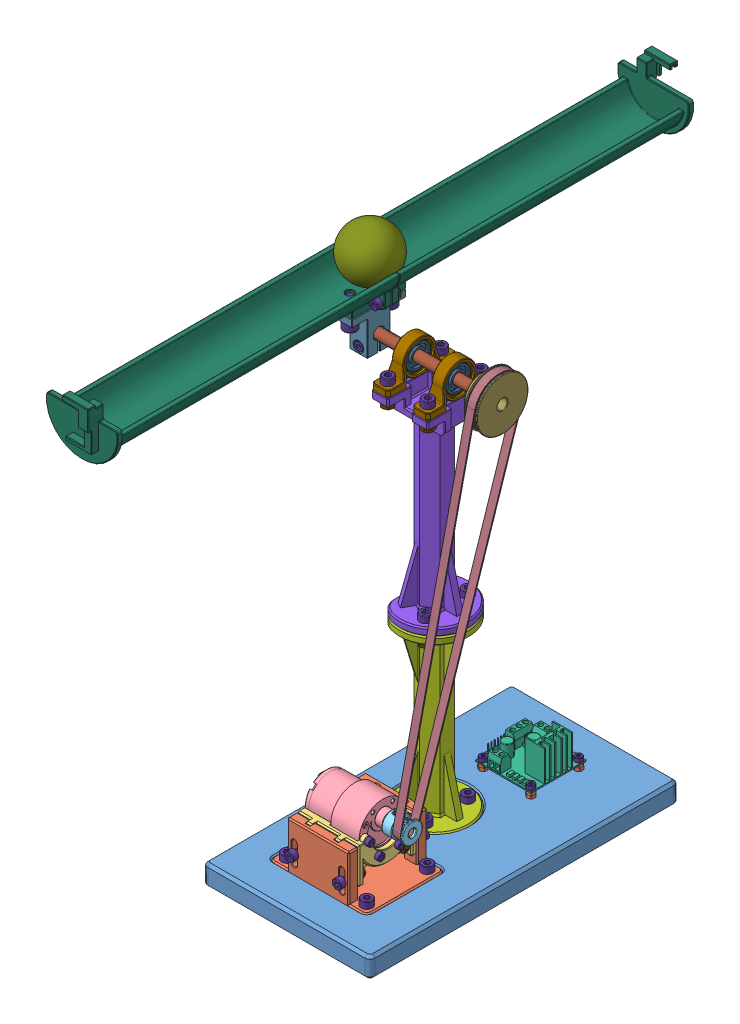
SolidWorks assembly ball and beam assembly, configuration Default. Lengths in mm.
Overall size (160.01 394.6 464.4).
84 component instances, 20 part files, 193 mates.
Components (placement in the parent):
- mount-1: mount [Default] at (98.4579 141.4502 221.2931) size (130 16 240)
- motor slider-1: motor slider [Default] at (95.4579 157.4502 283.2931) size (76 41 61)
- motor frame-1: motor frame [Default] at (93.2579 192.9369 283.2931) size (48 31 53)
- JGB37-520 motor-1: JGB37-520 motor [Default] at (115.4579 192.9369 283.2931) x (0 0 -1) z (1 0 0) size (37 37 70.88)
- 6mm 20-teeth gear-1: 6mm 20-teeth gear [Default] at (122.4579 199.9369 283.2931) x (0 0 -1) z (0 1 0) size (16.01 16 16.01)
- L298N driver-1: L298N driver [Default] at (119.9579 162.2502 172.7931) x (0 0 1) z (-1 0 0) size (43 25 43)
- lower pillar-1: lower pillar [Default] at (85.4579 151.4502 213.2931) size (54 138 54)
- upper pillar-1: upper pillar [Default] at (85.4579 289.4502 213.2931) size (49 150 54)
- bearing frame-1: bearing frame [Default] at (69.8579 453.4502 213.2931) x (0 0 1) z (-1 0 0) size (54 27 13)
- bearing frame-2: bearing frame [Default] at (100.9579 453.4502 213.2931) x (0 0 -1) z (1 0 0) size (54 27 13)
- ball bearing-1: ball bearing [Default] at (69.8579 453.4502 213.2931) x (-1 0 0) z (0 -0.088939 -0.996037) size (6 19 19)
- ball bearing-2: ball bearing [Default] at (100.9579 453.4502 213.2931) x (1 0 0) z (0 -0.000004 1) size (6 19 19)
- shaft-1: shaft [Default] at (78.4579 453.4502 213.2931) x (1 0 0) z (0 -0.931517 -0.363698) size (100 8 8)
- 8mm 60-teeth gear-1: 8mm 60-teeth gear [Default] at (120.4579 453.4502 213.2931) x (0 0 -1) z (0 1 0) size (40 16 40)
- timing belt-1: timing belt [Default] at (135.9579 199.9369 283.2931) x (0 0.963929 -0.26616) z (0 0.26616 0.963929) size (289.55 6 39.3)
- holder-1: holder [Default] at (42.4579 467.0502 213.2931) x (0 0 1) z (-1 0 0) size (42 32.6 14)
- half guide-1: half guide [Default] at (35.4579 505.0502 213.2931) size (55.43 48 232.2)
- half guide-2: half guide [Default] at (35.4579 505.0502 213.2931) x (-1 0 0) z (0 0 -1) size (55.43 48 232.2)
- ball-1: ball [Default] at (35.4579 504.8502 213.2931) x (0.673328 -0.738892 -0.025844) z (-0.222182 -0.168881 -0.960268) size (40 40 40)
- socket head cap screw_din-39: socket head cap screw_din [DIN 912 M6 x 16 --- 16N] at (35.4579 461.0502 228.7931) x (0 1 0) z (-0.089233 0 0.996011) size (22 10 10)
- socket head cap screw_din-40: socket head cap screw_din [DIN 912 M6 x 16 --- 16N] at (35.4579 461.0502 197.7931) x (0 1 0) z (0.266539 0 0.963824) size (22 10 10)
- socket head cap screw_din-23: socket head cap screw_din [DIN 912 M5 x 16 --- 16N] at (126.4579 162.4502 259.7931) x (0 -1 0) z (0.988894 0 -0.14862) size (21 8.5 8.5)
- socket head cap screw_din-24: socket head cap screw_din [DIN 912 M5 x 16 --- 16N] at (126.4579 162.4502 306.7931) x (0 -1 0) z (-0.960711 0 0.277552) size (21 8.5 8.5)
- socket head cap screw_din-25: socket head cap screw_din [DIN 912 M5 x 16 --- 16N] at (64.4579 162.4502 306.7931) x (0 -1 0) z (0.875234 0 -0.4837) size (21 8.5 8.5)
- socket head cap screw_din-26: socket head cap screw_din [DIN 912 M5 x 16 --- 16N] at (64.4579 162.4502 259.7931) x (0 -1 0) z (0.980307 0 0.197478) size (21 8.5 8.5)
- socket head cap screw_din-27: socket head cap screw_din [DIN 912 M5 x 16 --- 16N] at (94.9579 162.4502 229.7476) x (0 -1 0) z (0.778512 0 -0.62763) size (21 8.5 8.5)
- socket head cap screw_din-28: socket head cap screw_din [DIN 912 M5 x 16 --- 16N] at (66.4579 162.4502 213.2931) x (0 -1 0) z (0.181274 0 0.983433) size (21 8.5 8.5)
- socket head cap screw_din-29: socket head cap screw_din [DIN 912 M5 x 16 --- 16N] at (94.9579 162.4502 196.8386) x (0 -1 0) z (0.963689 0 -0.267027) size (21 8.5 8.5)
- hex nut style 1 gradeab_din-14: hex nut style 1 gradeab_din [Hexagon Nut ISO 4032 - M5 - D - N] at (64.4579 141.7502 259.7931) x (-0.560846 0 -0.82792) z (0 -1 0) size (8 9.24 4.7)
- hex nut style 1 gradeab_din-15: hex nut style 1 gradeab_din [Hexagon Nut ISO 4032 - M5 - D - N] at (126.4579 141.7502 259.7931) x (0.993337 0 0.115248) z (0 -1 0) size (8 9.24 4.7)
- hex nut style 1 gradeab_din-16: hex nut style 1 gradeab_din [Hexagon Nut ISO 4032 - M5 - D - N] at (126.4579 141.7502 306.7931) x (0.982792 0 -0.184716) z (0 -1 0) size (8 9.24 4.7)
- hex nut style 1 gradeab_din-17: hex nut style 1 gradeab_din [Hexagon Nut ISO 4032 - M5 - D - N] at (64.4579 141.7502 306.7931) x (0.998993 0 0.044877) z (0 -1 0) size (8 9.24 4.7)
- hex nut style 1 gradeab_din-22: hex nut style 1 gradeab_din [Hexagon Nut ISO 4032 - M5 - D - N] at (66.4579 146.4502 213.2931) x (0.894625 0 0.446817) z (0 1 0) size (8 9.24 4.7)
- hex nut style 1 gradeab_din-23: hex nut style 1 gradeab_din [Hexagon Nut ISO 4032 - M5 - D - N] at (94.9579 146.4502 196.8386) x (-0.894625 0 -0.446817) z (0 1 0) size (8 9.24 4.7)
- hex nut style 1 gradeab_din-24: hex nut style 1 gradeab_din [Hexagon Nut ISO 4032 - M5 - D - N] at (94.9579 146.4502 229.7476) x (0.894625 0 0.446817) z (0 1 0) size (8 9.24 4.7)
- socket head cap screw_din-44: socket head cap screw_din [DIN 912 M5 x 16 --- 16N] at (94.9579 300.4502 229.7476) x (0 -1 0) z (0.181274 0 0.983433) size (21 8.5 8.5)
- socket head cap screw_din-47: socket head cap screw_din [DIN 912 M5 x 16 --- 16N] at (94.9579 300.4502 196.8386) x (0 -1 0) z (0.83914 0 -0.543915) size (21 8.5 8.5)
- hex nut style 1 gradeab_din-28: hex nut style 1 gradeab_din [Hexagon Nut ISO 4032 - M5 - D - N] at (94.9579 278.7502 196.8386) x (0.993337 0 0.115248) z (0 -1 0) size (8 9.24 4.7)
- hex nut style 1 gradeab_din-29: hex nut style 1 gradeab_din [Hexagon Nut ISO 4032 - M5 - D - N] at (94.9579 278.7502 229.7476) x (0.993337 0 0.115248) z (0 -1 0) size (8 9.24 4.7)
- socket head cap screw_din-30: socket head cap screw_din [DIN 912 M5 x 16 --- 16N] at (69.9579 449.4502 192.7931) x (0 -1 0) z (0 0 1) size (21 8.5 8.5)
- socket head cap screw_din-31: socket head cap screw_din [DIN 912 M5 x 16 --- 16N] at (100.9579 449.4502 233.7931) x (0 -1 0) z (0 0 1) size (21 8.5 8.5)
- socket head cap screw_din-32: socket head cap screw_din [DIN 912 M5 x 16 --- 16N] at (69.8579 449.4502 233.7931) x (0 -1 0) z (0 0 1) size (21 8.5 8.5)
- socket head cap screw_din-33: socket head cap screw_din [DIN 912 M5 x 16 --- 16N] at (100.9579 449.4502 192.7931) x (0 -1 0) z (-0.000002 0 1) size (21 8.5 8.5)
- hex nut style 1 gradeab_din-18: hex nut style 1 gradeab_din [Hexagon Nut ISO 4032 - M5 - D - N] at (69.9579 433.4502 192.7931) x (-0.247009 0 -0.969013) z (0 1 0) size (8 9.24 4.7)
- hex nut style 1 gradeab_din-19: hex nut style 1 gradeab_din [Hexagon Nut ISO 4032 - M5 - D - N] at (69.8579 433.4502 233.7931) x (-0.247009 0 -0.969013) z (0 1 0) size (8 9.24 4.7)
- hex nut style 1 gradeab_din-20: hex nut style 1 gradeab_din [Hexagon Nut ISO 4032 - M5 - D - N] at (100.9579 428.7502 192.7931) x (-0.247009 0 0.969013) z (0 -1 0) size (8 9.24 4.7)
- hex nut style 1 gradeab_din-21: hex nut style 1 gradeab_din [Hexagon Nut ISO 4032 - M5 - D - N] at (100.9579 428.7502 233.7931) x (-0.247009 0 0.969013) z (0 -1 0) size (8 9.24 4.7)
- socket head cap screw_din-15: socket head cap screw_din [DIN 912 M4 x 16 --- 16N] at (113.9579 170.4369 317.7931) x (0 0 -1) z (0.995609 -0.093607 0) size (20 7 7)
- socket head cap screw_din-16: socket head cap screw_din [DIN 912 M4 x 16 --- 16N] at (76.9579 170.4369 317.7931) x (0 0 -1) z (0.955528 0.2949 0) size (20 7 7)
- socket head cap screw_din-17: socket head cap screw_din [DIN 912 M4 x 16 --- 16N] at (76.9579 170.4369 248.7931) x (0 0 1) z (-0.883816 -0.467834 0) size (20 7 7)
- socket head cap screw_din-18: socket head cap screw_din [DIN 912 M4 x 16 --- 16N] at (113.9579 170.4369 248.7931) x (0 0 1) z (0.883816 0.467834 0) size (20 7 7)
- hex nut style 1 gradeab_din-10: hex nut style 1 gradeab_din [Hexagon Nut ISO 4032 - M4 - D - N] at (113.9579 170.4369 301.8931) x (-0.247009 0.969013 0) z (0 0 1) size (7 8.08 3.2)
- hex nut style 1 gradeab_din-11: hex nut style 1 gradeab_din [Hexagon Nut ISO 4032 - M4 - D - N] at (113.9579 170.4369 264.6931) x (0.857592 0.514331 0) z (0 0 -1) size (7 8.08 3.2)
- hex nut style 1 gradeab_din-12: hex nut style 1 gradeab_din [Hexagon Nut ISO 4032 - M4 - D - N] at (76.9579 170.4369 267.8931) size (7 8.08 3.2)
- hex nut style 1 gradeab_din-13: hex nut style 1 gradeab_din [Hexagon Nut ISO 4032 - M4 - D - N] at (76.9579 170.4369 298.6931) x (-0.934219 0.356701 0) z (0 0 -1) size (7 8.08 3.2)
- socket head cap screw_din-42: socket head cap screw_din [DIN 912 M4 x 16 --- 16N] at (23.4579 479.5566 222.7931) x (0 0 -1) z (0.771294 -0.636479 0) size (20 7 7)
- socket head cap screw_din-41: socket head cap screw_din [DIN 912 M4 x 16 --- 16N] at (47.4579 479.5566 222.7931) x (0 0 -1) z (0.771294 -0.636479 0) size (20 7 7)
- hex nut style 1 gradeab_din-25: hex nut style 1 gradeab_din [Hexagon Nut ISO 4032 - M4 - D - N] at (23.4579 479.5566 204.5931) x (-0.554504 0.832181 0) z (0 0 -1) size (7 8.08 3.2)
- hex nut style 1 gradeab_din-27: hex nut style 1 gradeab_din [Hexagon Nut ISO 4032 - M4 - D - N] at (47.4579 479.5566 204.5931) x (-0.554504 0.832181 0) z (0 0 -1) size (7 8.08 3.2)
- socket head cap screw_din-43: socket head cap screw_din [DIN 912 M4 x 16 --- 16N] at (35.4579 445.4502 222.2931) x (0 0 -1) z (0.771294 -0.636479 0) size (20 7 7)
- socket set screw flat point_din-1: socket set screw flat point_din [DIN 913 - M4 x 5-N] at (126.2079 207.9369 283.2931) x (0 -1 0) z (-0.046067 0 0.998938) size (5 4 4)
- socket set screw flat point_din-2: socket set screw flat point_din [DIN 913 - M4 x 5-N] at (126.2079 199.9369 275.2931) x (0 0 1) z (-0.067896 -0.997692 0) size (5 4 4)
- socket set screw flat point_din-3: socket set screw flat point_din [DIN 913 - M4 x 5-N] at (125.4579 462.4502 213.2931) x (0 -1 0) z (0.980778 0 0.195125) size (5 4 4)
- socket set screw flat point_din-4: socket set screw flat point_din [DIN 913 - M4 x 5-N] at (125.4579 453.4502 204.2931) x (0 0 1) z (0.974269 -0.22539 0) size (5 4 4)
- socket head cap screw_din-5: socket head cap screw_din [DIN 912 M3 x 16 --- 16N] at (116.9579 166.2502 169.7931) x (0 -1 0) z (-0.613586 0 -0.789628) size (19 5.5 5.5)
- socket head cap screw_din-7: socket head cap screw_din [DIN 912 M3 x 16 --- 16N] at (116.9579 166.2502 132.7931) x (0 -1 0) z (0 0 1) size (19 5.5 5.5)
- socket head cap screw_din-8: socket head cap screw_din [DIN 912 M3 x 16 --- 16N] at (79.9579 166.2502 169.7931) x (0 -1 0) z (-0.000315 0 1) size (19 5.5 5.5)
- socket head cap screw_din-9: socket head cap screw_din [DIN 912 M3 x 16 --- 16N] at (79.9579 166.2502 132.7931) x (0 -1 0) z (0 0 1) size (19 5.5 5.5)
- hex nut style 1 gradeab_iso-11: hex nut style 1 gradeab_iso [ISO - 4032 - M3 - D - N] at (116.9579 159.8502 132.7931) x (0.674492 0 -0.738282) z (0 -1 0) size (5.5 6.35 2.4)
- hex nut style 1 gradeab_iso-12: hex nut style 1 gradeab_iso [ISO - 4032 - M3 - D - N] at (116.9579 159.8502 169.7931) x (0.674492 0 -0.738282) z (0 -1 0) size (5.5 6.35 2.4)
- hex nut style 1 gradeab_iso-13: hex nut style 1 gradeab_iso [ISO - 4032 - M3 - D - N] at (79.9579 159.8502 169.7931) x (0.674492 0 -0.738282) z (0 -1 0) size (5.5 6.35 2.4)
- hex nut style 1 gradeab_iso-14: hex nut style 1 gradeab_iso [ISO - 4032 - M3 - D - N] at (79.9579 159.8502 132.7931) x (0.674492 0 -0.738282) z (0 -1 0) size (5.5 6.35 2.4)
- hex nut style 1 gradeab_iso-1: hex nut style 1 gradeab_iso [ISO - 4032 - M3 - D - N] at (79.9579 159.8502 169.7931) x (1 0 0) z (0 1 0) size (5.5 6.35 2.4)
- hex nut style 1 gradeab_iso-3: hex nut style 1 gradeab_iso [ISO - 4032 - M3 - D - N] at (116.9579 159.8502 132.7931) x (1 0 0) z (0 1 0) size (5.5 6.35 2.4)
- hex nut style 1 gradeab_iso-4: hex nut style 1 gradeab_iso [ISO - 4032 - M3 - D - N] at (116.9579 157.4502 169.7931) x (0.674492 0 -0.738282) z (0 -1 0) size (5.5 6.35 2.4)
- hex nut style 1 gradeab_iso-5: hex nut style 1 gradeab_iso [ISO - 4032 - M3 - D - N] at (79.9579 159.8502 132.7931) x (1 0 0) z (0 1 0) size (5.5 6.35 2.4)
- hex nut style 1 gradeab_iso-6: hex nut style 1 gradeab_iso [ISO - 4032 - M3 - D - N] at (116.9579 152.4502 169.7931) x (-0.966898 0 -0.255164) z (0 1 0) size (5.5 6.35 2.4)
- hex nut style 1 gradeab_iso-7: hex nut style 1 gradeab_iso [ISO - 4032 - M3 - D - N] at (79.9579 152.4502 169.7931) x (0.901145 0 -0.433517) z (0 1 0) size (5.5 6.35 2.4)
- hex nut style 1 gradeab_iso-8: hex nut style 1 gradeab_iso [ISO - 4032 - M3 - D - N] at (79.9579 152.4502 132.7931) x (0.990081 0 -0.140499) z (0 1 0) size (5.5 6.35 2.4)
- hex nut style 1 gradeab_iso-9: hex nut style 1 gradeab_iso [ISO - 4032 - M3 - D - N] at (116.9579 152.4502 132.7931) x (0.649349 0 -0.76049) z (0 1 0) size (5.5 6.35 2.4)
- socket head cap screw_din-34: socket head cap screw_din [DIN 912 M3 x 12 --- 12N] at (122.4579 179.5135 291.0431) x (-1 0 0) z (0 -0.924225 -0.381849) size (15 5.5 5.5)
- socket head cap screw_din-35: socket head cap screw_din [DIN 912 M3 x 12 --- 12N] at (122.4579 179.5135 275.5431) x (-1 0 0) z (0 -0.924225 -0.381849) size (15 5.5 5.5)
- socket head cap screw_din-36: socket head cap screw_din [DIN 912 M3 x 12 --- 12N] at (122.4579 192.9369 298.7931) x (-1 0 0) z (0 -0.924225 -0.381849) size (15 5.5 5.5)
- socket head cap screw_din-37: socket head cap screw_din [DIN 912 M3 x 12 --- 12N] at (122.4579 192.9369 267.7931) x (-1 0 0) z (0 -0.924225 -0.381849) size (15 5.5 5.5)
Mates (geometry in assembly coordinates):
- Concentric1: concentric: cylinder of mount-1 through (126.4579 141.4502 306.7931) axis (0 1 0) radius 2.6; cylinder of motor slider-1 through (126.4579 88.8643 306.7931) axis (0 1 0) radius 2.6
- Concentric2: concentric: cylinder of mount-1 through (64.4579 141.4502 259.7931) axis (0 1 0) radius 2.6; cylinder of motor slider-1 through (64.4579 88.8643 259.7931) axis (0 1 0) radius 2.6
- Coincident2: coincident: plane of motor slider-1 through (95.4579 157.4502 283.2931) normal (0 0 1); plane of motor frame-1 through (93.2579 192.9369 283.2931) normal (0 0 1)
- Tangent1: tangent: plane of motor slider-1 through (111.9079 177.9502 252.7931) normal (1 0 0); cylinder of motor frame-1 through (113.9579 170.4369 260.6911) axis (0 0 1) radius 2.05
- Coincident4: coincident: plane of motor slider-1 through (119.4579 157.4502 283.2931) normal (1 0 0); plane of motor frame-1 through (119.4579 192.9369 267.7931) normal (1 0 0)
- Coincident5: coincident: plane of motor slider-1 through (71.4579 157.4502 283.2931) normal (-1 0 0); plane of motor frame-1 through (71.4579 192.9369 260.6931) normal (-1 0 0)
- LimitDistance2: limit distance = 0.5133 mm: axis of motor frame-1 through (113.9579 170.4369 302.3931) axis (0 0 1); axis of motor slider-1 through (113.9579 170.9502 253.2931) axis (0 0 1)
- Coincident6: coincident: axis of motor frame-1 through (111.9579 192.9369 283.2931) axis (-1 0 0); axis of JGB37-520 motor-1 through (93.4579 192.9369 283.2931) axis (1 0 0)
- Concentric3: concentric: cylinder of motor frame-1 through (71.4569 192.9369 298.7931) axis (1 0 0) radius 1.55; cylinder of JGB37-520 motor-1 through (115.4579 192.9369 298.7931) axis (1 0 0) radius 1.25
- Coincident7: coincident: plane of motor frame-1 through (115.4579 192.9369 267.7931) normal (-1 0 0); plane of JGB37-520 motor-1 through (115.4579 192.9369 283.2931) normal (1 0 0)
- Concentric4: concentric: cylinder of L298N driver-1 through (79.9579 163.2502 169.7931) axis (0 -1 0) radius 1.5; cylinder of mount-1 through (79.9579 141.4502 169.7931) axis (0 1 0) radius 1.55
- Concentric5: concentric: cylinder of mount-1 through (116.9579 141.4502 169.7931) axis (0 1 0) radius 1.55; cylinder of L298N driver-1 through (116.9579 163.2502 169.7931) axis (0 -1 0) radius 1.5
- Concentric6: concentric: cylinder of mount-1 through (116.9579 141.4502 169.7931) axis (0 1 0) radius 1.55; cylinder of socket head cap screw_din-5 through (116.9579 198.0002 169.7931) axis (0 1 0) radius 1.5
- Coincident9: coincident: plane of L298N driver-1 through (119.9579 163.2502 172.7931) normal (0 1 0); plane of socket head cap screw_din-5 through (114.7865 163.2502 171.4804) normal (0 -1 0)
- Concentric7: concentric: cylinder of mount-1 through (116.9579 141.4502 132.7931) axis (0 1 0) radius 1.55; cylinder of socket head cap screw_din-7 through (116.9579 198.0002 132.7931) axis (0 1 0) radius 1.5
- Concentric8: concentric: cylinder of mount-1 through (79.9579 141.4502 132.7931) axis (0 1 0) radius 1.55; cylinder of socket head cap screw_din-9 through (79.9579 198.0002 132.7931) axis (0 1 0) radius 1.5
- Concentric9: concentric: cylinder of mount-1 through (79.9579 141.4502 169.7931) axis (0 1 0) radius 1.55; cylinder of socket head cap screw_din-8 through (79.9579 198.0002 169.7931) axis (0 1 0) radius 1.5
- Coincident10: coincident: plane of L298N driver-1 through (119.9579 163.2502 172.7931) normal (0 1 0); plane of socket head cap screw_din-7 through (119.7079 163.2502 132.7931) normal (0 -1 0)
- Coincident11: coincident: plane of L298N driver-1 through (119.9579 163.2502 172.7931) normal (0 1 0); plane of socket head cap screw_din-9 through (82.7079 163.2502 132.7931) normal (0 -1 0)
- Coincident12: coincident: plane of L298N driver-1 through (119.9579 163.2502 172.7931) normal (0 1 0); plane of socket head cap screw_din-8 through (82.7079 163.2502 169.7939) normal (0 -1 0)
- Concentric10: concentric: cylinder of socket head cap screw_din-5 through (116.9579 198.0002 169.7931) axis (0 1 0) radius 1.5; cylinder of hex nut style 1 gradeab_iso-4 through (116.9579 159.8502 169.7931) axis (0 -1 0) radius 1.25
- Coincident13: coincident: plane of mount-1 through (98.4579 157.4502 221.2931) normal (0 1 0); plane of hex nut style 1 gradeab_iso-4 through (119.3023 157.4502 171.9349) normal (0 -1 0)
- Coincident14: coincident: plane of mount-1 through (98.4579 157.4502 221.2931) normal (0 1 0); plane of hex nut style 1 gradeab_iso-3 through (116.9579 157.4502 129.6176) normal (0 -1 0)
- Concentric11: concentric: cylinder of socket head cap screw_din-7 through (116.9579 198.0002 132.7931) axis (0 1 0) radius 1.5; cylinder of hex nut style 1 gradeab_iso-3 through (116.9579 157.4502 132.7931) axis (0 1 0) radius 1.25
- Coincident15: coincident: plane of mount-1 through (98.4579 157.4502 221.2931) normal (0 1 0); plane of hex nut style 1 gradeab_iso-5 through (79.9579 157.4502 129.6176) normal (0 -1 0)
- Concentric12: concentric: cylinder of socket head cap screw_din-9 through (79.9579 198.0002 132.7931) axis (0 1 0) radius 1.5; cylinder of hex nut style 1 gradeab_iso-5 through (79.9579 157.4502 132.7931) axis (0 1 0) radius 1.25
- Coincident16: coincident: plane of mount-1 through (98.4579 157.4502 221.2931) normal (0 1 0); plane of hex nut style 1 gradeab_iso-1 through (79.9579 157.4502 166.6176) normal (0 -1 0)
- Concentric13: concentric: cylinder of socket head cap screw_din-8 through (79.9579 198.0002 169.7931) axis (0 1 0) radius 1.5; cylinder of hex nut style 1 gradeab_iso-1 through (79.9579 157.4502 169.7931) axis (0 1 0) radius 1.25
- Concentric14: concentric: cylinder of socket head cap screw_din-5 through (116.9579 198.0002 169.7931) axis (0 1 0) radius 1.5; cylinder of hex nut style 1 gradeab_iso-6 through (116.9579 150.0502 169.7931) axis (0 1 0) radius 1.25
- Concentric15: concentric: cylinder of socket head cap screw_din-7 through (116.9579 198.0002 132.7931) axis (0 1 0) radius 1.5; cylinder of hex nut style 1 gradeab_iso-9 through (116.9579 150.0502 132.7931) axis (0 1 0) radius 1.25
- Concentric16: concentric: cylinder of socket head cap screw_din-9 through (79.9579 198.0002 132.7931) axis (0 1 0) radius 1.5; cylinder of hex nut style 1 gradeab_iso-8 through (79.9579 150.0502 132.7931) axis (0 1 0) radius 1.25
- Concentric17: concentric: cylinder of socket head cap screw_din-8 through (79.9579 198.0002 169.7931) axis (0 1 0) radius 1.5; cylinder of hex nut style 1 gradeab_iso-7 through (79.9579 150.0502 169.7931) axis (0 1 0) radius 1.25
- Coincident27: coincident: plane of mount-1 through (98.4579 151.4502 221.2931) normal (0 1 0); plane of motor slider-1 through (119.4579 151.4502 252.7931) normal (0 -1 0)
- Concentric293: concentric: cylinder of socket head cap screw_din-5 through (116.9579 198.0002 169.7931) axis (0 1 0) radius 1.5; cylinder of hex nut style 1 gradeab_iso-12 through (116.9579 162.2502 169.7931) axis (0 -1 0) radius 1.25
- Coincident353: coincident: plane of hex nut style 1 gradeab_iso-4 through (119.3023 159.8502 171.9349) normal (0 1 0); plane of hex nut style 1 gradeab_iso-12 through (119.3023 159.8502 171.9349) normal (0 -1 0)
- Coincident354: coincident: plane of hex nut style 1 gradeab_iso-1 through (79.9579 159.8502 166.6176) normal (0 1 0); plane of hex nut style 1 gradeab_iso-13 through (82.3023 159.8502 171.9349) normal (0 -1 0)
- Concentric294: concentric: cylinder of socket head cap screw_din-8 through (79.9579 198.0002 169.7931) axis (0 1 0) radius 1.5; cylinder of hex nut style 1 gradeab_iso-13 through (79.9579 162.2502 169.7931) axis (0 -1 0) radius 1.25
- Concentric295: concentric: cylinder of socket head cap screw_din-7 through (116.9579 198.0002 132.7931) axis (0 1 0) radius 1.5; cylinder of hex nut style 1 gradeab_iso-11 through (116.9579 162.2502 132.7931) axis (0 -1 0) radius 1.25
- Coincident355: coincident: plane of hex nut style 1 gradeab_iso-3 through (116.9579 159.8502 129.6176) normal (0 1 0); plane of hex nut style 1 gradeab_iso-11 through (119.3023 159.8502 134.9349) normal (0 -1 0)
- Coincident356: coincident: plane of hex nut style 1 gradeab_iso-5 through (79.9579 159.8502 129.6176) normal (0 1 0); plane of hex nut style 1 gradeab_iso-14 through (82.3023 159.8502 134.9349) normal (0 -1 0)
- Concentric296: concentric: cylinder of socket head cap screw_din-9 through (79.9579 198.0002 132.7931) axis (0 1 0) radius 1.5; cylinder of hex nut style 1 gradeab_iso-14 through (79.9579 162.2502 132.7931) axis (0 -1 0) radius 1.25
- Coincident357: coincident: plane of L298N driver-1 through (119.9579 162.2502 172.7931) normal (0 -1 0); plane of hex nut style 1 gradeab_iso-12 through (119.3023 162.2502 171.9349) normal (0 1 0)
- Concentric297: concentric: cylinder of JGB37-520 motor-1 through (136.9579 199.9369 283.2931) axis (-1 0 0) radius 3; cylinder of 6mm 20-teeth gear-1 through (122.4579 199.9369 283.2931) axis (-1 0 0) radius 3
- Distance1: distance = 1 mm: plane of JGB37-520 motor-1 through (121.4579 199.9369 283.2931) normal (1 0 0); plane of 6mm 20-teeth gear-1 through (122.4579 199.9369 283.2931) normal (-1 0 0)
- Concentric298: concentric: cylinder of 6mm 20-teeth gear-1 through (122.4579 199.9369 283.2931) axis (-1 0 0) radius 3; cylinder of timing belt-1 through (129.9579 199.9369 283.2931) axis (1 0 0) radius 6.1
- Coincident361: coincident: plane of 6mm 20-teeth gear-1 through (129.9579 199.9369 283.2931) normal (1 0 0); plane of timing belt-1 through (129.9579 453.4502 213.2931) normal (-1 0 0)
- Concentric299: concentric: cylinder of timing belt-1 through (129.9579 453.4502 213.2931) axis (1 0 0) radius 18.85; cylinder of 8mm 60-teeth gear-1 through (138.4579 453.4502 213.2931) axis (1 0 0) radius 4
- Coincident362: coincident: plane of timing belt-1 through (129.9579 453.4502 213.2931) normal (-1 0 0); plane of 8mm 60-teeth gear-1 through (129.9579 453.4502 213.2931) normal (1 0 0)
- Concentric300: concentric: cylinder of 6mm 20-teeth gear-1 through (126.2079 207.9369 283.2931) axis (0 1 0) radius 2; cylinder of socket set screw flat point_din-1 through (126.2079 220.6369 283.2931) axis (0 1 0) radius 2
- Tangent3: tangent: cylinder of JGB37-520 motor-1 through (136.9579 199.9369 283.2931) axis (-1 0 0) radius 3; plane of socket set screw flat point_din-1 through (127.4566 202.9369 283.3507) normal (0 -1 0)
- Concentric301: concentric: cylinder of 6mm 20-teeth gear-1 through (126.2079 199.9369 275.2931) axis (0 0 -1) radius 2; cylinder of socket set screw flat point_din-2 through (126.2079 199.9369 262.5931) axis (0 0 -1) radius 2
- Tangent4: tangent: cylinder of JGB37-520 motor-1 through (136.9579 199.9369 283.2931) axis (-1 0 0) radius 3; plane of socket set screw flat point_din-2 through (124.9608 200.0218 280.2931) normal (0 0 1)
- Parallel2: parallel: axis of 8mm 60-teeth gear-1 through (125.4579 459.7316 213.2931) axis (0 1 0); axis of socket set screw flat point_din-1 through (126.2079 203.6869 283.2931) axis (0 1 0)
- Concentric302: concentric: cylinder of 8mm 60-teeth gear-1 through (125.4579 467.4502 213.2931) axis (0 1 0) radius 2; cylinder of socket set screw flat point_din-3 through (125.4579 475.1502 213.2931) axis (0 1 0) radius 2
- Tangent5: tangent: cylinder of 8mm 60-teeth gear-1 through (138.4579 453.4502 213.2931) axis (1 0 0) radius 4; plane of socket set screw flat point_din-3 through (125.7019 457.4502 212.0671) normal (0 -1 0)
- Concentric303: concentric: cylinder of 8mm 60-teeth gear-1 through (125.4579 453.4502 199.2931) axis (0 0 -1) radius 2; cylinder of socket set screw flat point_din-4 through (125.4579 453.4502 191.5931) axis (0 0 -1) radius 2
- Tangent6: tangent: cylinder of 8mm 60-teeth gear-1 through (138.4579 453.4502 213.2931) axis (1 0 0) radius 4; plane of socket set screw flat point_din-4 through (125.1762 452.2324 209.2931) normal (0 0 1)
- Concentric304: concentric: cylinder of bearing frame-1 through (65.3579 453.4502 213.2931) axis (1 0 0) radius 9.5; cylinder of ball bearing-1 through (90.4954 453.4502 213.2931) axis (-1 0 0) radius 9.5
- Coincident363: coincident: plane of bearing frame-1 through (69.8579 453.4502 213.2931) normal (-1 0 0); plane of ball bearing-1 through (69.8579 453.4502 213.2931) normal (-1 0 0)
- Concentric305: concentric: cylinder of bearing frame-2 through (105.4579 453.4502 213.2931) axis (-1 0 0) radius 9.5; cylinder of ball bearing-2 through (80.3204 453.4502 213.2931) axis (1 0 0) radius 9.5
- Coincident364: coincident: plane of bearing frame-2 through (100.9579 453.4502 213.2931) normal (1 0 0); plane of ball bearing-2 through (100.9579 453.4502 213.2931) normal (1 0 0)
- Concentric306: concentric: cylinder of 8mm 60-teeth gear-1 through (138.4579 453.4502 213.2931) axis (1 0 0) radius 4; cylinder of ball bearing-1 through (90.4954 453.4502 213.2931) axis (-1 0 0) radius 4
- Concentric307: concentric: cylinder of ball bearing-1 through (90.4954 453.4502 213.2931) axis (-1 0 0) radius 4; cylinder of ball bearing-2 through (80.3204 453.4502 213.2931) axis (1 0 0) radius 4
- Parallel3: parallel: plane of mount-1 through (98.4579 157.4502 221.2931) normal (0 1 0); plane of bearing frame-1 through (69.8579 439.4502 213.2931) normal (0 -1 0)
- Parallel4: parallel: plane of mount-1 through (98.4579 157.4502 221.2931) normal (0 1 0); plane of bearing frame-2 through (100.9579 439.4502 213.2931) normal (0 -1 0)
- Concentric308: concentric: cylinder of motor frame-1 through (113.9579 170.4369 260.6911) axis (0 0 1) radius 2.05; cylinder of socket head cap screw_din-15 through (113.9579 170.4369 349.5431) axis (0 0 1) radius 2
- Coincident369: coincident: plane of motor slider-1 through (119.4579 151.4502 313.7931) normal (0 0 1); plane of socket head cap screw_din-15 through (114.2856 173.9216 313.7931) normal (0 0 -1)
- Coincident371: coincident: plane of motor frame-1 through (93.2579 192.9369 301.8931) normal (0 0 -1); plane of hex nut style 1 gradeab_din-10 through (110.0417 169.4387 301.8931) normal (0 0 1)
- Concentric309: concentric: cylinder of socket head cap screw_din-15 through (113.9579 170.4369 349.5431) axis (0 0 1) radius 2; cylinder of hex nut style 1 gradeab_din-10 through (113.9579 170.4369 298.6931) axis (0 0 1) radius 1.65
- Concentric310: concentric: cylinder of motor frame-1 through (76.9579 170.4369 260.6911) axis (0 0 1) radius 2.05; cylinder of socket head cap screw_din-16 through (76.9579 170.4369 349.5431) axis (0 0 1) radius 2
- Coincident372: coincident: plane of motor slider-1 through (119.4579 151.4502 313.7931) normal (0 0 1); plane of socket head cap screw_din-16 through (75.9258 173.7813 313.7931) normal (0 0 -1)
- Concentric311: concentric: cylinder of motor frame-1 through (76.9579 170.4369 309.7951) axis (0 0 -1) radius 2.05; cylinder of socket head cap screw_din-17 through (76.9579 170.4369 217.0431) axis (0 0 -1) radius 2
- Coincident373: coincident: plane of motor slider-1 through (119.4579 192.4502 252.7931) normal (0 0 -1); plane of socket head cap screw_din-17 through (75.3205 173.5303 252.7931) normal (0 0 1)
- Concentric312: concentric: cylinder of motor frame-1 through (113.9579 170.4369 309.7951) axis (0 0 -1) radius 2.05; cylinder of socket head cap screw_din-18 through (113.9579 170.4369 217.0431) axis (0 0 -1) radius 2
- Coincident374: coincident: plane of motor slider-1 through (119.4579 192.4502 252.7931) normal (0 0 -1); plane of socket head cap screw_din-18 through (115.5954 167.3436 252.7931) normal (0 0 1)
- Coincident378: coincident: plane of motor frame-1 through (93.2579 192.9369 301.8931) normal (0 0 -1); plane of hex nut style 1 gradeab_din-13 through (78.3995 174.2125 301.8931) normal (0 0 1)
- Concentric313: concentric: cylinder of socket head cap screw_din-16 through (76.9579 170.4369 349.5431) axis (0 0 1) radius 2; cylinder of hex nut style 1 gradeab_din-13 through (76.9579 170.4369 301.8931) axis (0 0 -1) radius 1.65
- Coincident379: coincident: plane of motor frame-1 through (93.2579 192.9369 264.6931) normal (0 0 1); plane of hex nut style 1 gradeab_din-12 through (76.9579 174.4784 264.6931) normal (0 0 -1)
- Concentric314: concentric: cylinder of socket head cap screw_din-17 through (76.9579 170.4369 217.0431) axis (0 0 -1) radius 2; cylinder of hex nut style 1 gradeab_din-12 through (76.9579 170.4369 264.6931) axis (0 0 1) radius 1.65
- Coincident380: coincident: plane of motor frame-1 through (93.2579 192.9369 264.6931) normal (0 0 1); plane of hex nut style 1 gradeab_din-11 through (116.0366 166.971 264.6931) normal (0 0 -1)
- Concentric315: concentric: cylinder of socket head cap screw_din-18 through (113.9579 170.4369 217.0431) axis (0 0 -1) radius 2; cylinder of hex nut style 1 gradeab_din-11 through (113.9579 170.4369 267.8931) axis (0 0 -1) radius 1.65
- Concentric324: concentric: cylinder of motor slider-1 through (126.4579 88.8643 306.7931) axis (0 1 0) radius 2.6; cylinder of socket head cap screw_din-24 through (126.4579 194.2002 306.7931) axis (0 1 0) radius 2.5
- Concentric325: concentric: cylinder of motor slider-1 through (126.4579 88.8643 259.7931) axis (0 1 0) radius 2.6; cylinder of socket head cap screw_din-23 through (126.4579 194.2002 259.7931) axis (0 1 0) radius 2.5
- Concentric326: concentric: cylinder of motor slider-1 through (64.4579 88.8643 306.7931) axis (0 1 0) radius 2.6; cylinder of socket head cap screw_din-25 through (64.4579 194.2002 306.7931) axis (0 1 0) radius 2.5
- Concentric327: concentric: cylinder of motor slider-1 through (64.4579 88.8643 259.7931) axis (0 1 0) radius 2.6; cylinder of socket head cap screw_din-26 through (64.4579 194.2002 259.7931) axis (0 1 0) radius 2.5
- Coincident389: coincident: plane of motor slider-1 through (119.4579 157.4502 305.9931) normal (0 1 0); plane of socket head cap screw_din-24 through (127.6375 157.4502 310.8761) normal (0 -1 0)
- Coincident390: coincident: plane of motor slider-1 through (119.4579 157.4502 305.9931) normal (0 1 0); plane of socket head cap screw_din-23 through (125.8263 157.4502 255.5903) normal (0 -1 0)
- Coincident391: coincident: plane of motor slider-1 through (119.4579 157.4502 305.9931) normal (0 1 0); plane of socket head cap screw_din-26 through (65.2972 157.4502 255.6268) normal (0 -1 0)
- Coincident392: coincident: plane of motor slider-1 through (119.4579 157.4502 305.9931) normal (0 1 0); plane of socket head cap screw_din-25 through (62.4022 157.4502 303.0733) normal (0 -1 0)
- Concentric328: concentric: cylinder of socket head cap screw_din-25 through (64.4579 194.2002 306.7931) axis (0 1 0) radius 2.5; cylinder of hex nut style 1 gradeab_din-17 through (64.4579 146.4502 306.7931) axis (0 -1 0) radius 2.1
- Concentric329: concentric: cylinder of socket head cap screw_din-24 through (126.4579 194.2002 306.7931) axis (0 1 0) radius 2.5; cylinder of hex nut style 1 gradeab_din-16 through (126.4579 146.4502 306.7931) axis (0 -1 0) radius 2.1
- Concentric330: concentric: cylinder of socket head cap screw_din-23 through (126.4579 194.2002 259.7931) axis (0 1 0) radius 2.5; cylinder of hex nut style 1 gradeab_din-15 through (126.4579 146.4502 259.7931) axis (0 -1 0) radius 2.1
- Concentric331: concentric: cylinder of socket head cap screw_din-26 through (64.4579 194.2002 259.7931) axis (0 1 0) radius 2.5; cylinder of hex nut style 1 gradeab_din-14 through (64.4579 146.4502 259.7931) axis (0 -1 0) radius 2.1
- Coincident393: coincident: plane of mount-1 through (98.4579 146.4502 221.2931) normal (0 -1 0); plane of hex nut style 1 gradeab_din-17 through (64.2507 146.4502 311.4072) normal (0 1 0)
- Coincident394: coincident: plane of mount-1 through (98.4579 146.4502 221.2931) normal (0 -1 0); plane of hex nut style 1 gradeab_din-14 through (68.2819 146.4502 257.2026) normal (0 1 0)
- Coincident395: coincident: plane of mount-1 through (98.4579 146.4502 221.2931) normal (0 -1 0); plane of hex nut style 1 gradeab_din-16 through (127.3111 146.4502 311.3324) normal (0 1 0)
- Coincident396: coincident: plane of mount-1 through (98.4579 146.4502 221.2931) normal (0 -1 0); plane of hex nut style 1 gradeab_din-15 through (125.9256 146.4502 264.3811) normal (0 1 0)
- Parallel8: parallel: axis of mount-1 through (85.4579 151.4502 213.2931) axis (0 1 0); axis of 6mm 20-teeth gear-1 through (126.2079 203.4209 283.2931) axis (0 1 0)
- Coincident402: coincident: plane of bearing frame-2 through (100.9579 439.4502 213.2931) normal (0 -1 0); plane of upper pillar-1 through (107.4579 439.4502 227.2931) normal (0 1 0)
- Concentric344: concentric: cylinder of 8mm 60-teeth gear-1 through (138.4579 453.4502 213.2931) axis (1 0 0) radius 4; cylinder of shaft-1 through (128.4579 453.4502 213.2931) axis (-1 0 0) radius 4
- Coincident406: coincident: plane of bearing frame-1 through (69.8579 439.4502 213.2931) normal (0 -1 0); plane of upper pillar-1 through (76.4579 439.4502 227.2931) normal (0 1 0)
- Coincident412: coincident: plane of upper pillar-1 through (85.4579 433.4502 213.2931) normal (0 -1 0); plane of hex nut style 1 gradeab_din-21 through (96.4823 433.4502 232.6522) normal (0 1 0)
- Coincident413: coincident: plane of upper pillar-1 through (85.4579 433.4502 213.2931) normal (0 -1 0); plane of hex nut style 1 gradeab_din-19 through (65.3823 433.4502 234.934) normal (0 1 0)
- Coincident414: coincident: plane of upper pillar-1 through (85.4579 433.4502 213.2931) normal (0 -1 0); plane of hex nut style 1 gradeab_din-20 through (96.4823 433.4502 191.6522) normal (0 1 0)
- Coincident415: coincident: plane of upper pillar-1 through (85.4579 433.4502 213.2931) normal (0 -1 0); plane of hex nut style 1 gradeab_din-18 through (65.4823 433.4502 193.934) normal (0 1 0)
- Concentric371: concentric: cylinder of mount-1 through (66.4579 141.4502 213.2931) axis (0 1 0) radius 2.6; cylinder of socket head cap screw_din-28 through (66.4579 194.2002 213.2931) axis (0 1 0) radius 2.5
- Concentric372: concentric: cylinder of mount-1 through (94.9579 141.4502 229.7476) axis (0 1 0) radius 2.6; cylinder of socket head cap screw_din-27 through (94.9579 194.2002 229.7476) axis (0 1 0) radius 2.5
- Concentric373: concentric: cylinder of mount-1 through (94.9579 141.4502 196.8386) axis (0 1 0) radius 2.6; cylinder of socket head cap screw_din-29 through (94.9579 194.2002 196.8386) axis (0 1 0) radius 2.5
- Concentric376: concentric: cylinder of socket head cap screw_din-27 through (94.9579 194.2002 229.7476) axis (0 1 0) radius 2.5; cylinder of hex nut style 1 gradeab_din-24 through (94.9579 141.7502 229.7476) axis (0 1 0) radius 2.1
- Coincident421: coincident: plane of mount-1 through (98.4579 146.4502 221.2931) normal (0 -1 0); plane of hex nut style 1 gradeab_din-24 through (97.0217 146.4502 225.6155) normal (0 1 0)
- Coincident422: coincident: plane of mount-1 through (98.4579 146.4502 221.2931) normal (0 -1 0); plane of hex nut style 1 gradeab_din-23 through (92.8942 146.4502 200.9707) normal (0 1 0)
- Concentric377: concentric: cylinder of socket head cap screw_din-29 through (94.9579 194.2002 196.8386) axis (0 1 0) radius 2.5; cylinder of hex nut style 1 gradeab_din-23 through (94.9579 141.7502 196.8386) axis (0 1 0) radius 2.1
- Concentric379: concentric: cylinder of socket head cap screw_din-28 through (66.4579 194.2002 213.2931) axis (0 1 0) radius 2.5; cylinder of hex nut style 1 gradeab_din-22 through (66.4579 141.7502 213.2931) axis (0 1 0) radius 2.1
- Coincident424: coincident: plane of mount-1 through (98.4579 146.4502 221.2931) normal (0 -1 0); plane of hex nut style 1 gradeab_din-22 through (68.5217 146.4502 209.161) normal (0 1 0)
- Coincident426: coincident: plane of mount-1 through (98.4579 152.4502 221.2931) normal (0 -1 0); plane of hex nut style 1 gradeab_iso-6 through (116.1477 152.4502 172.8634) normal (0 1 0)
- Coincident427: coincident: plane of mount-1 through (98.4579 152.4502 221.2931) normal (0 -1 0); plane of hex nut style 1 gradeab_iso-9 through (114.5431 152.4502 130.7311) normal (0 1 0)
- Coincident428: coincident: plane of mount-1 through (98.4579 152.4502 221.2931) normal (0 -1 0); plane of hex nut style 1 gradeab_iso-8 through (79.5118 152.4502 129.6491) normal (0 1 0)
- Coincident429: coincident: plane of mount-1 through (98.4579 152.4502 221.2931) normal (0 -1 0); plane of hex nut style 1 gradeab_iso-7 through (78.5813 152.4502 166.9315) normal (0 1 0)
- Coincident431: coincident: plane of bearing frame-2 through (100.9579 444.4502 213.2931) normal (0 1 0); plane of socket head cap screw_din-31 through (105.2079 444.4502 233.7931) normal (0 -1 0)
- Coincident432: coincident: plane of bearing frame-1 through (69.8579 444.4502 213.2931) normal (0 1 0); plane of socket head cap screw_din-32 through (74.1079 444.4502 233.7931) normal (0 -1 0)
- Coincident433: coincident: plane of bearing frame-2 through (100.9579 444.4502 213.2931) normal (0 1 0); plane of socket head cap screw_din-33 through (105.2079 444.4502 192.7931) normal (0 -1 0)
- Coincident434: coincident: plane of bearing frame-1 through (69.8579 444.4502 213.2931) normal (0 1 0); plane of socket head cap screw_din-30 through (74.2079 444.4502 192.7931) normal (0 -1 0)
- Concentric380: concentric: cylinder of hex nut style 1 gradeab_din-19 through (69.8579 428.7502 233.7931) axis (0 1 0) radius 2.1; cylinder of socket head cap screw_din-32 through (69.8579 481.2002 233.7931) axis (0 1 0) radius 2.5
- Concentric381: concentric: cylinder of bearing frame-1 through (69.8579 439.4492 233.7931) axis (0 1 0) radius 2.6; cylinder of socket head cap screw_din-32 through (69.8579 481.2002 233.7931) axis (0 1 0) radius 2.5
- Parallel18: parallel: cylinder of upper pillar-1 through (69.9579 289.4492 233.7931) axis (0 1 0) radius 2.6; cylinder of socket head cap screw_din-32 through (69.8579 481.2002 233.7931) axis (0 1 0) radius 2.5
- Concentric383: concentric: cylinder of upper pillar-1 through (69.9579 289.4492 192.7931) axis (0 1 0) radius 2.6; cylinder of socket head cap screw_din-30 through (69.9579 481.2002 192.7931) axis (0 1 0) radius 2.5
- Concentric384: concentric: cylinder of hex nut style 1 gradeab_din-18 through (69.9579 428.7502 192.7931) axis (0 1 0) radius 2.1; cylinder of socket head cap screw_din-30 through (69.9579 481.2002 192.7931) axis (0 1 0) radius 2.5
- Tangent9: tangent: cylinder of socket head cap screw_din-30 through (69.9579 481.2002 192.7931) axis (0 1 0) radius 2.5; cylinder of bearing frame-1 through (69.8579 439.4492 192.7931) axis (0 1 0) radius 2.6
- Concentric386: concentric: cylinder of hex nut style 1 gradeab_din-20 through (100.9579 433.4502 192.7931) axis (0 -1 0) radius 2.1; cylinder of socket head cap screw_din-33 through (100.9579 481.2002 192.7931) axis (0 1 0) radius 2.5
- Concentric387: concentric: cylinder of upper pillar-1 through (100.9579 289.4492 192.7931) axis (0 1 0) radius 2.6; cylinder of socket head cap screw_din-33 through (100.9579 481.2002 192.7931) axis (0 1 0) radius 2.5
- Concentric388: concentric: cylinder of hex nut style 1 gradeab_din-21 through (100.9579 433.4502 233.7931) axis (0 -1 0) radius 2.1; cylinder of socket head cap screw_din-31 through (100.9579 481.2002 233.7931) axis (0 1 0) radius 2.5
- Concentric389: concentric: cylinder of upper pillar-1 through (100.9579 289.4492 233.7931) axis (0 1 0) radius 2.6; cylinder of socket head cap screw_din-31 through (100.9579 481.2002 233.7931) axis (0 1 0) radius 2.5
- Concentric390: concentric: cylinder of bearing frame-2 through (100.9579 439.4492 233.7931) axis (0 1 0) radius 2.6; cylinder of socket head cap screw_din-31 through (100.9579 481.2002 233.7931) axis (0 1 0) radius 2.5
- Concentric392: concentric: cylinder of bearing frame-2 through (100.9579 439.4492 192.7931) axis (0 1 0) radius 2.6; cylinder of socket head cap screw_din-33 through (100.9579 481.2002 192.7931) axis (0 1 0) radius 2.5
- Concentric393: concentric: cylinder of JGB37-520 motor-1 through (115.4579 192.9369 298.7931) axis (1 0 0) radius 1.25; cylinder of socket head cap screw_din-36 through (154.2079 192.9369 298.7931) axis (1 0 0) radius 1.5
- Concentric394: concentric: cylinder of motor frame-1 through (71.4569 192.9369 298.7931) axis (1 0 0) radius 1.55; cylinder of socket head cap screw_din-36 through (154.2079 192.9369 298.7931) axis (1 0 0) radius 1.5
- Coincident435: coincident: plane of motor frame-1 through (119.4579 192.9369 267.7931) normal (1 0 0); plane of socket head cap screw_din-36 through (119.4579 193.987 296.2515) normal (-1 0 0)
- Coincident436: coincident: plane of motor frame-1 through (119.4579 192.9369 267.7931) normal (1 0 0); plane of socket head cap screw_din-34 through (119.4579 180.5636 288.5015) normal (-1 0 0)
- Concentric395: concentric: cylinder of JGB37-520 motor-1 through (115.4579 179.5135 291.0431) axis (1 0 0) radius 1.25; cylinder of socket head cap screw_din-34 through (154.2079 179.5135 291.0431) axis (1 0 0) radius 1.5
- Coincident438: coincident: plane of motor frame-1 through (119.4579 192.9369 267.7931) normal (1 0 0); plane of socket head cap screw_din-37 through (119.4579 193.987 265.2515) normal (-1 0 0)
- Coincident439: coincident: plane of motor frame-1 through (119.4579 192.9369 267.7931) normal (1 0 0); plane of socket head cap screw_din-35 through (119.4579 180.5636 273.0015) normal (-1 0 0)
- Concentric397: concentric: cylinder of JGB37-520 motor-1 through (115.4579 192.9369 267.7931) axis (1 0 0) radius 1.25; cylinder of socket head cap screw_din-37 through (154.2079 192.9369 267.7931) axis (1 0 0) radius 1.5
- Concentric398: concentric: cylinder of JGB37-520 motor-1 through (115.4579 179.5135 275.5431) axis (1 0 0) radius 1.25; cylinder of socket head cap screw_din-35 through (154.2079 179.5135 275.5431) axis (1 0 0) radius 1.5
- Concentric399: concentric: cylinder of motor frame-1 through (71.4569 179.5135 291.0431) axis (1 0 0) radius 1.55; cylinder of socket head cap screw_din-34 through (154.2079 179.5135 291.0431) axis (1 0 0) radius 1.5
- Concentric400: concentric: cylinder of motor frame-1 through (71.4569 179.5135 275.5431) axis (1 0 0) radius 1.55; cylinder of socket head cap screw_din-35 through (154.2079 179.5135 275.5431) axis (1 0 0) radius 1.5
- Concentric401: concentric: cylinder of motor frame-1 through (71.4569 192.9369 267.7931) axis (1 0 0) radius 1.55; cylinder of socket head cap screw_din-37 through (154.2079 192.9369 267.7931) axis (1 0 0) radius 1.5
- Concentric402: concentric: cylinder of shaft-1 through (128.4579 453.4502 213.2931) axis (-1 0 0) radius 4; cylinder of holder-1 through (42.4589 453.4502 213.2931) axis (-1 0 0) radius 4
- Distance3: distance = 10 mm: plane of shaft-1 through (128.4579 453.4502 213.2931) normal (1 0 0); plane of 8mm 60-teeth gear-1 through (138.4579 453.4502 213.2931) normal (1 0 0)
- Coincident444: coincident: plane of holder-1 through (28.4579 473.0502 234.2931) normal (0 1 0); plane of half guide-1 through (35.4579 473.0502 213.2931) normal (0 -1 0)
- Coincident445: coincident: plane of holder-1 through (28.4579 473.0502 234.2931) normal (0 1 0); plane of half guide-2 through (35.4579 473.0502 213.2931) normal (0 -1 0)
- Coincident446: coincident: plane of half guide-1 through (35.4579 505.0502 213.2931) normal (0 0 -1); plane of half guide-2 through (35.4579 505.0502 213.2931) normal (0 0 1)
- Tangent10: tangent: cylinder of half guide-1 through (35.4579 505.0502 437.2931) axis (0 0 -1) radius 20.2; sphere of ball-1
- Tangent11: tangent: sphere of ball-1; cylinder of half guide-2 through (35.4579 505.0502 -10.7069) axis (0 0 1) radius 20.2
- LimitDistance4: limit distance = 200 mm: sphere of ball-1; plane of half guide-1 through (35.4579 505.0502 433.2931) normal (0 0 -1)
- Concentric405: concentric: cylinder of holder-1 through (35.4579 440.4492 197.7931) axis (0 1 0) radius 3; cylinder of socket head cap screw_din-40 through (35.4579 429.3002 197.7931) axis (0 -1 0) radius 3
- Coincident447: coincident: plane of holder-1 through (28.4579 467.0502 192.2931) normal (0 -1 0); plane of socket head cap screw_din-40 through (30.6388 467.0502 199.1258) normal (0 1 0)
- Concentric406: concentric: cylinder of holder-1 through (35.4579 440.4492 228.7931) axis (0 1 0) radius 3; cylinder of socket head cap screw_din-39 through (35.4579 429.3002 228.7931) axis (0 -1 0) radius 3
- Coincident448: coincident: plane of holder-1 through (28.4579 467.0502 222.2931) normal (0 -1 0); plane of socket head cap screw_din-39 through (30.4779 467.0502 228.3469) normal (0 1 0)
- Concentric4071: concentric: cylinder of half guide-1 through (47.4579 479.5566 437.2941) axis (0 0 -1) radius 2.05; cylinder of half guide-2 through (47.4579 479.5566 -10.7079) axis (0 0 1) radius 2.05
- Concentric4081: concentric: cylinder of half guide-1 through (23.4579 479.5566 437.2941) axis (0 0 -1) radius 2.05; cylinder of half guide-2 through (23.4579 479.5566 -10.7079) axis (0 0 1) radius 2.05
- Concentric4091: concentric: cylinder of half guide-1 through (47.4579 479.5566 437.2941) axis (0 0 -1) radius 2.05; cylinder of socket head cap screw_din-41 through (47.4579 479.5566 254.5431) axis (0 0 1) radius 2
- Coincident4491: coincident: plane of half guide-1 through (35.4579 505.0502 218.7931) normal (0 0 1); plane of socket head cap screw_din-41 through (49.6856 482.2561 218.7931) normal (0 0 -1)
- Concentric4101: concentric: cylinder of half guide-1 through (23.4579 479.5566 437.2941) axis (0 0 -1) radius 2.05; cylinder of socket head cap screw_din-42 through (23.4579 479.5566 254.5431) axis (0 0 1) radius 2
- Coincident4501: coincident: plane of half guide-1 through (35.4579 505.0502 218.7931) normal (0 0 1); plane of socket head cap screw_din-42 through (25.6856 482.2561 218.7931) normal (0 0 -1)
- Concentric4111: concentric: cylinder of socket head cap screw_din-42 through (23.4579 479.5566 254.5431) axis (0 0 1) radius 2; cylinder of hex nut style 1 gradeab_din-25 through (23.4579 479.5566 207.7931) axis (0 0 -1) radius 1.65
- Coincident4511: coincident: plane of half guide-2 through (35.4579 505.0502 207.7931) normal (0 0 -1); plane of hex nut style 1 gradeab_din-25 through (26.8212 481.7976 207.7931) normal (0 0 1)
- Concentric4131: concentric: cylinder of holder-1 through (35.4579 440.4492 197.7931) axis (0 1 0) radius 3; cylinder of half guide-2 through (35.4579 509.0512 197.7931) axis (0 -1 0) radius 2.8
- Concentric4141: concentric: cylinder of holder-1 through (35.4579 440.4492 228.7931) axis (0 1 0) radius 3; cylinder of half guide-1 through (35.4579 509.0512 228.7931) axis (0 -1 0) radius 2.8
- Coincident4541: coincident: plane of shaft-1 through (28.4579 453.4502 213.2931) normal (-1 0 0); plane of holder-1 through (28.4579 467.0502 213.2931) normal (-1 0 0)
- Coincident4561: coincident: plane of half guide-2 through (35.4579 505.0502 207.7931) normal (0 0 -1); plane of hex nut style 1 gradeab_din-27 through (50.8212 481.7976 207.7931) normal (0 0 1)
- Concentric4161: concentric: cylinder of socket head cap screw_din-41 through (47.4579 479.5566 254.5431) axis (0 0 1) radius 2; cylinder of hex nut style 1 gradeab_din-27 through (47.4579 479.5566 207.7931) axis (0 0 -1) radius 1.65
- Concentric4171: concentric: cylinder of holder-1 through (35.4579 445.4502 192.2931) axis (0 0 1) radius 2; cylinder of socket head cap screw_din-43 through (35.4579 445.4502 254.0431) axis (0 0 1) radius 2
- Coincident4571: coincident: plane of holder-1 through (35.4579 445.4502 218.2931) normal (0 0 1); plane of socket head cap screw_din-43 through (37.6856 448.1498 218.2931) normal (0 0 -1)
- LimitAngle2: limit planar angle = 1.570796 rad: plane of half guide-1 through (35.4579 505.0502 437.2931) normal (0 0 1); plane of upper pillar-1 through (94.4579 427.4502 227.2931) normal (0 1 0)
- Coincident4572: coincident: plane of upper pillar-1 through (85.4579 289.4502 213.2931) normal (0 -1 0); plane of lower pillar-1 through (85.4579 289.4502 213.2931) normal (0 1 0)
- Concentric4172: concentric: cylinder of upper pillar-1 through (85.4579 295.4502 213.2931) axis (0 -1 0) radius 27; cylinder of lower pillar-1 through (85.4579 289.4502 213.2931) axis (0 -1 0) radius 27
- Concentric4173: concentric: cylinder of upper pillar-1 through (94.9579 289.4492 196.8386) axis (0 1 0) radius 2.6; cylinder of lower pillar-1 through (94.9579 151.4492 196.8386) axis (0 1 0) radius 2.6
- Concentric4174: concentric: cylinder of upper pillar-1 through (94.9579 289.4492 229.7476) axis (0 1 0) radius 2.6; cylinder of lower pillar-1 through (94.9579 151.4492 229.7476) axis (0 1 0) radius 2.6
- Concentric4176: concentric: cylinder of mount-1 through (85.4579 151.4502 213.2931) axis (0 1 0) radius 27.1; cylinder of lower pillar-1 through (85.4579 157.4502 213.2931) axis (0 -1 0) radius 27
- Coincident4573: coincident: plane of mount-1 through (85.4579 151.4502 213.2931) normal (0 1 0); plane of lower pillar-1 through (85.4579 151.4502 213.2931) normal (0 -1 0)
- Concentric4177: concentric: cylinder of socket head cap screw_din-27 through (94.9579 194.2002 229.7476) axis (0 1 0) radius 2.5; cylinder of lower pillar-1 through (94.9579 151.4492 229.7476) axis (0 1 0) radius 2.6
- Concentric4178: concentric: cylinder of socket head cap screw_din-28 through (66.4579 194.2002 213.2931) axis (0 1 0) radius 2.5; cylinder of lower pillar-1 through (66.4579 151.4492 213.2931) axis (0 1 0) radius 2.6
- Concentric4179: concentric: cylinder of socket head cap screw_din-29 through (94.9579 194.2002 196.8386) axis (0 1 0) radius 2.5; cylinder of lower pillar-1 through (94.9579 151.4492 196.8386) axis (0 1 0) radius 2.6
- Coincident4574: coincident: plane of socket head cap screw_din-29 through (93.8231 157.4502 192.7429) normal (0 -1 0); plane of lower pillar-1 through (85.4579 157.4502 213.2931) normal (0 1 0)
- Coincident4575: coincident: plane of socket head cap screw_din-28 through (70.6375 157.4502 212.5227) normal (0 -1 0); plane of lower pillar-1 through (85.4579 157.4502 213.2931) normal (0 1 0)
- Coincident4576: coincident: plane of socket head cap screw_din-27 through (92.2905 157.4502 226.4389) normal (0 -1 0); plane of lower pillar-1 through (85.4579 157.4502 213.2931) normal (0 1 0)
- Concentric41801: concentric: cylinder of upper pillar-1 through (94.9579 289.4492 229.7476) axis (0 1 0) radius 2.6; cylinder of socket head cap screw_din-44 through (94.9579 332.2002 229.7476) axis (0 1 0) radius 2.5
- Coincident45771: coincident: plane of upper pillar-1 through (85.4579 295.4502 213.2931) normal (0 1 0); plane of socket head cap screw_din-44 through (99.1375 295.4502 228.9771) normal (0 -1 0)
- Concentric41811: concentric: cylinder of upper pillar-1 through (94.9579 289.4492 196.8386) axis (0 1 0) radius 2.6; cylinder of socket head cap screw_din-47 through (94.9579 332.2002 196.8386) axis (0 1 0) radius 2.5
- Coincident4581: coincident: plane of lower pillar-1 through (85.4579 283.4502 213.2931) normal (0 -1 0); plane of hex nut style 1 gradeab_din-29 through (94.4256 283.4502 234.3356) normal (0 1 0)
- Concentric4184: concentric: cylinder of socket head cap screw_din-44 through (94.9579 332.2002 229.7476) axis (0 1 0) radius 2.5; cylinder of hex nut style 1 gradeab_din-29 through (94.9579 283.4502 229.7476) axis (0 -1 0) radius 2.1
- Concentric4185: concentric: cylinder of socket head cap screw_din-47 through (94.9579 332.2002 196.8386) axis (0 1 0) radius 2.5; cylinder of hex nut style 1 gradeab_din-28 through (94.9579 283.4502 196.8386) axis (0 -1 0) radius 2.1
- Coincident4582: coincident: plane of lower pillar-1 through (85.4579 283.4502 213.2931) normal (0 -1 0); plane of hex nut style 1 gradeab_din-28 through (94.4256 283.4502 201.4266) normal (0 1 0)
